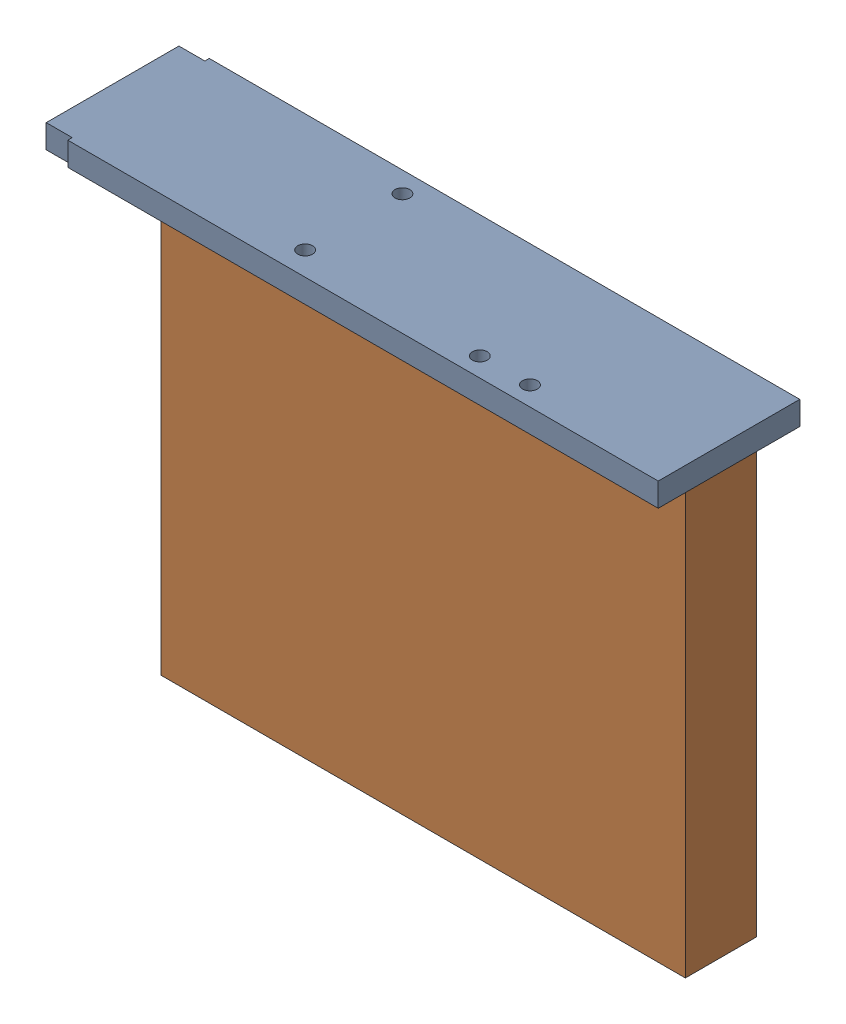
SolidWorks assembly chargerBatPCB, configuration Default. Lengths in mm.
Overall size (41.81 30.81 9.6).
2 component instances, 2 part files, 1 mates.
Components (placement in the parent):
- chargerPCB-1: chargerPCB [Default] at (7.0807 8.4215 6.9172) size (41.81 1.6 9.6)
- chargerBattery-1: chargerBattery [Default] at (9.1427 -23.8144 15.789) x (1 0 0) z (0 1 0) size (35.56 4.83 29.21)
Mates (geometry in assembly coordinates):
- Lock2: lock: unknown of chargerPCB-1; unknown of chargerBattery-1
